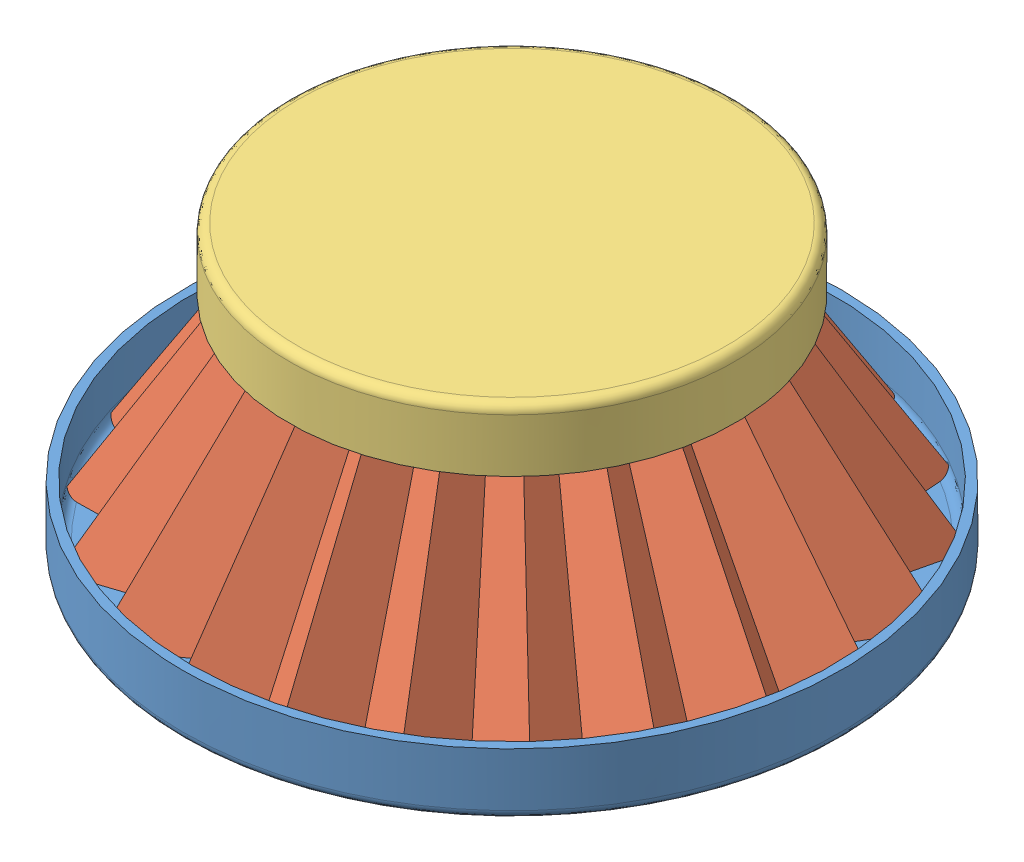
SolidWorks assembly Air Filter Assembly, configuration Default. Lengths in mm.
Overall size (97.19 32 97.12).
3 component instances, 3 part files, 4 mates.
Components (placement in the parent):
- Air Filter Bottom Cap-1: Air Filter Bottom Cap [Default] at (12.2303 31.2594 67.5444) size (74 7 74)
- Air Filter Mesh-1: Air Filter Mesh [Default] at (12.2303 32.2594 67.5444) x (0.863922 0 -0.503625) z (0.503625 0 0.863922) size (71.14 30 70.94)
- Air Filter top Cap-1: Air Filter top Cap [Default] at (12.2303 63.2594 67.5444) x (0.210101 0 0.97768) z (0.97768 0 -0.210101) size (50 7 50)
Mates (geometry in assembly coordinates):
- Concentric1: concentric aligned: cylinder of Air Filter Bottom Cap-1 through (12.2303 32.2594 67.5444) axis (0 1 0) radius 36; circle of Air Filter Mesh-1
- Coincident1: coincident anti-aligned: plane of Air Filter Bottom Cap-1 through (12.2303 32.2594 67.5444) normal (0 1 0); plane of Air Filter Mesh-1 through (12.2303 32.2594 67.5444) normal (0 -1 0)
- Concentric2: concentric anti-aligned: cylinder of Air Filter Bottom Cap-1 through (12.2303 38.2594 67.5444) axis (0 -1 0) radius 37; cylinder of Air Filter top Cap-1 through (12.2303 56.2594 67.5444) axis (0 1 0) radius 25
- Coincident3: coincident anti-aligned: plane of Air Filter Mesh-1 through (12.2303 62.2594 67.5444) normal (0 1 0); plane of Air Filter top Cap-1 through (12.2303 62.2594 67.5444) normal (0 -1 0)
